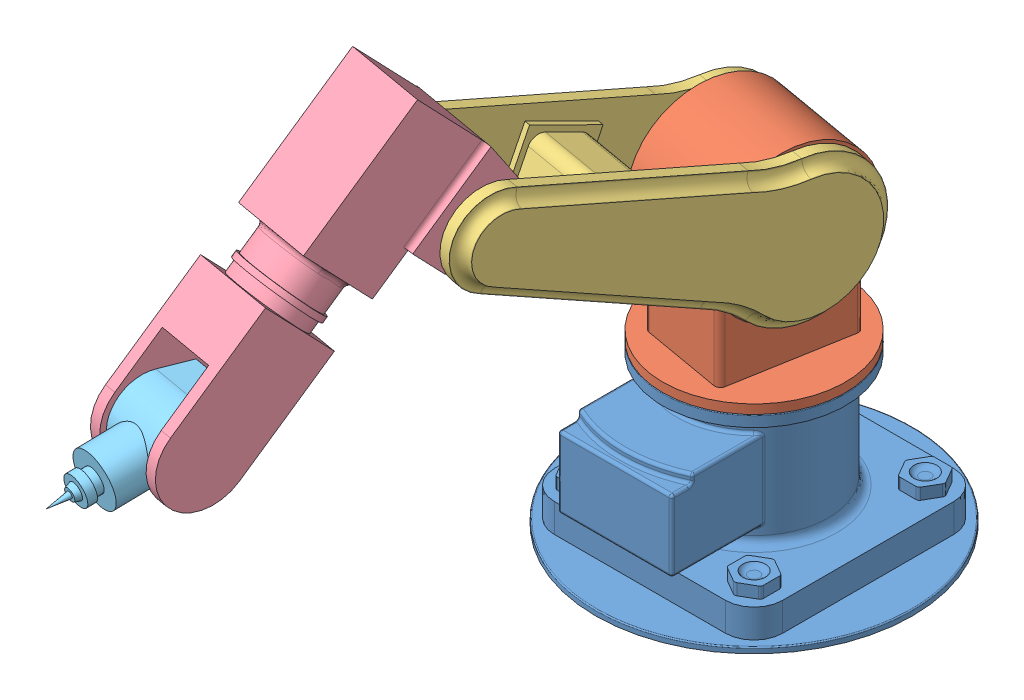
SolidWorks assembly MONTAJ SON, configuration Varsayılan. Lengths in mm.
Overall size (555 903.07 1345.25).
5 component instances, 5 part files, 8 mates.
Components (placement in the parent):
- Parça1-1: Parça1 [Varsayılan] at (-11.1789 -183.8773 555) size (555 280 555)
- Parça2-1: Parça2 [Varsayılan] at (-11.1789 -23.8773 555) x (-0.172588 0 0.984994) z (-0.984994 0 -0.172588) size (320 466 320)
- Parça3-1: Parça3 [Varsayılan] at (-11.1789 312.1227 555) x (-0.064578 -0.927359 0.368557) z (0.160052 -0.374172 -0.913443) size (250 260.14 700)
- Parça4-1: Parça4 [Varsayılan] at (-107.1963 665.2744 1045.0473) x (-0.124083 -0.695057 0.708166) z (-0.984994 0 -0.172588) size (595 294.13 160)
- Parça5-1: Parça5 [Varsayılan] at (-122.4699 303.8447 1421.923) x (-0.16934 -0.193116 0.966453) z (-0.984994 0 -0.172588) size (275 130 100)
Mates (geometry in assembly coordinates):
- Eş Merkezli1: concentric: cylinder of Parça1-1 through (-11.1789 -103.8773 555) axis (0 1 0) radius 100; cylinder of Parça2-1 through (-11.1789 96.1227 555) axis (0 -1 0) radius 100
- Çakışık1: coincident: plane of Parça1-1 through (-11.1789 96.1227 555) normal (0 1 0); plane of Parça2-1 through (-11.1789 96.1227 555) normal (0 -1 0)
- Eş Merkezli2: concentric: cylinder of Parça2-1 through (71.7193 312.1227 590.0413) axis (-0.921091 0 -0.389347) radius 75; cylinder of Parça3-1 through (71.7193 312.1227 590.0413) axis (-0.921091 0 -0.389347) radius 75
- Çakışık2: coincident: plane of Parça2-1 through (71.7193 -23.8773 590.0413) normal (0.921091 0 0.389347); plane of Parça3-1 through (71.7193 312.1227 590.0413) normal (-0.921091 0 -0.389347)
- Eş Merkezli3: concentric: cylinder of Parça3-1 through (266.0062 280.6223 130.4106) axis (-0.921091 0 -0.389347) radius 50; cylinder of Parça4-1 through (266.0062 280.6223 130.4106) axis (-0.921091 0 -0.389347) radius 35
- Çakışık3: coincident: plane of Parça3-1; plane of Parça4-1
- Eş Merkezli4: concentric: cylinder of Parça4-1 through (355.9541 -57.9174 -159.4341) axis (-0.921091 0 -0.389347) radius 50; cylinder of Parça5-1 through (355.9541 -57.9174 -159.4341) axis (-0.921091 0 -0.389347) radius 50
- Çakışık4: coincident: plane of Parça4-1; plane of Parça5-1
